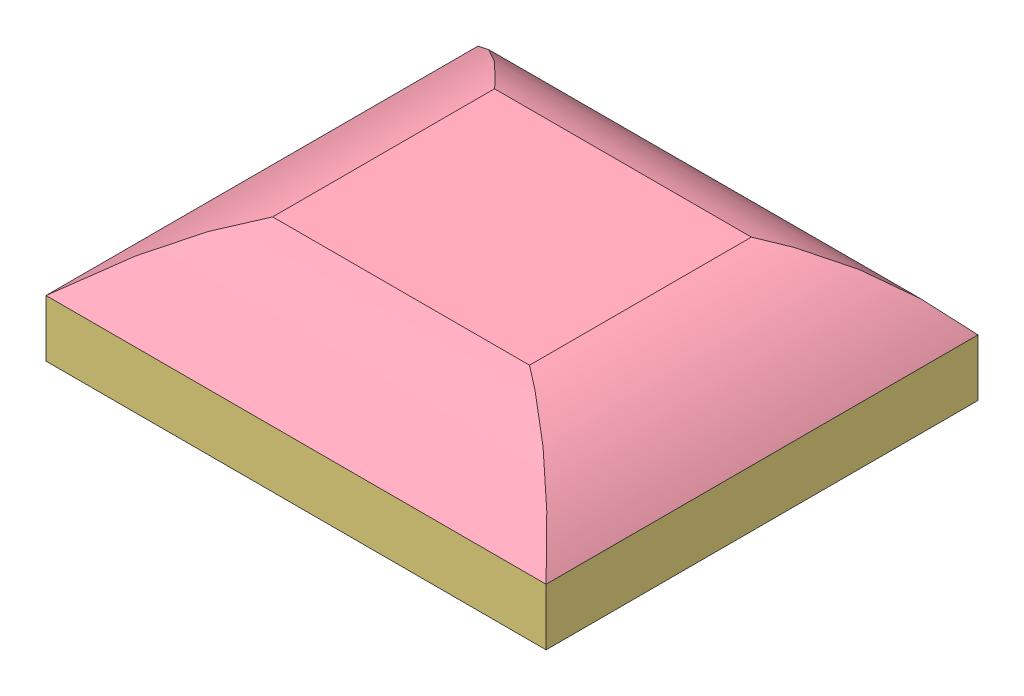
SolidWorks assembly Сборка1, configuration По умолчанию. Lengths in mm.
Overall size (11 2.93 9.5).
11 component instances, 4 part files, 11 mates.
Components (placement in the parent):
- Ntrcnjkbn-1: Ntrcnjkbn [По умолчанию] at (-3.4337 12.5234 -9.2376) size (10.5 0.3 9)
- Антенна-1: Антенна [По умолчанию] at (-7.1837 12.8234 -11.7376) size (2 0.4 3.88)
- Антенна-2: Антенна [По умолчанию] at (-4.6837 12.8234 -11.7376) size (2 0.4 3.88)
- Антенна-3: Антенна [По умолчанию] at (-2.1837 12.8234 -11.7376) size (2 0.4 3.88)
- Антенна-4: Антенна [По умолчанию] at (0.3163 12.8234 -11.7376) size (2 0.4 3.88)
- Антенна-5: Антенна [По умолчанию] at (0.3163 12.8234 -6.7376) x (-1 0 0) z (0 0 -1) size (2 0.4 3.88)
- Антенна-6: Антенна [По умолчанию] at (-2.1837 12.8234 -6.7376) x (-1 0 0) z (0 0 -1) size (2 0.4 3.88)
- Антенна-7: Антенна [По умолчанию] at (-4.6837 12.8234 -6.7376) x (-1 0 0) z (0 0 -1) size (2 0.4 3.88)
- Антенна-8: Антенна [По умолчанию] at (-7.1837 12.8234 -6.7376) x (-1 0 0) z (0 0 -1) size (2 0.4 3.88)
- Корпус-1: Корпус [По умолчанию] at (-3.4337 11.7734 -9.2035) size (11 1.25 9.5)
- Крышка-1: Крышка [По умолчанию] at (-3.4337 13.0234 -9.2035) size (11 1.68 9.5)
Mates (geometry in assembly coordinates):
- Концентричный1: concentric aligned: cylinder of Ntrcnjkbn-1 through (-7.1837 12.5234 -9.4876) axis (0 1 0) radius 0.125; cylinder of Антенна-1 through (-7.1837 12.5234 -9.4876) axis (0 1 0) radius 0.125
- Совпадение2: coincident anti-aligned: plane of Ntrcnjkbn-1 through (-3.4337 12.8234 -9.2376) normal (0 1 0); plane of Антенна-1 through (-7.1837 12.8234 -11.7376) normal (0 -1 0)
- Параллельность1: parallel aligned: plane of Ntrcnjkbn-1 through (-8.6837 12.8234 -4.7376) normal (-1 0 0); plane of Антенна-1 through (-8.1837 12.9234 -11.7376) normal (-1 0 0)
- Концентричный2: concentric aligned: cylinder of Ntrcnjkbn-1 through (0.3163 12.5234 -8.9876) axis (0 1 0) radius 0.125; cylinder of Антенна-5 through (0.3163 12.5234 -8.9876) axis (0 1 0) radius 0.125
- Совпадение6: coincident anti-aligned: plane of Ntrcnjkbn-1 through (-3.4337 12.8234 -9.2376) normal (0 1 0); plane of Антенна-5 through (0.3163 12.8234 -6.7376) normal (0 -1 0)
- Параллельность2: parallel aligned: plane of Ntrcnjkbn-1 through (1.8163 12.8234 -4.7376) normal (1 0 0); plane of Антенна-5 through (1.3163 12.9234 -6.7376) normal (1 0 0)
- Совпадение8: coincident anti-aligned: plane of Ntrcnjkbn-1 through (-8.6837 12.8234 -13.7376) normal (0 0 -1); plane of Корпус-1 through (-8.6837 13.0234 -13.7376) normal (0 0 1)
- Совпадение9: coincident anti-aligned: plane of Ntrcnjkbn-1 through (1.8163 12.8234 -4.7376) normal (1 0 0); plane of Корпус-1 through (1.8163 13.0234 -4.6694) normal (-1 0 0)
- Совпадение10: coincident anti-aligned: plane of Ntrcnjkbn-1 through (-3.4337 12.5234 -9.2376) normal (0 -1 0); plane of Корпус-1 through (-3.4337 12.5234 -9.2035) normal (0 1 0)
- Совпадение11: coincident aligned: line of Корпус-1 through (-8.9337 13.0234 -13.9535) axis (0 0 1); line of Крышка-1 through (-8.9337 13.0234 -13.9535) axis (0 0 1)
- Совпадение12: coincident aligned: line of Корпус-1 through (-8.9337 13.0234 -4.4535) axis (1 0 0); line of Крышка-1 through (-8.9337 13.0234 -4.4535) axis (1 0 0)
